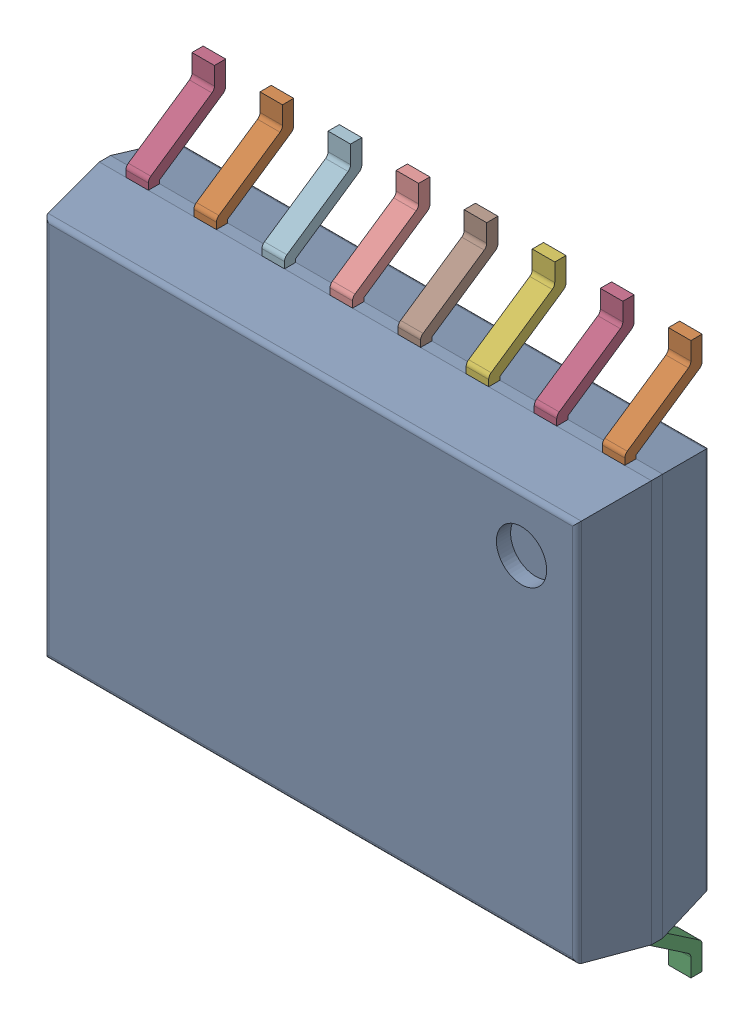
SolidWorks assembly IC6_3.step, configuration Default. Lengths in mm.
Overall size (10.3 10.3 2.65).
3 component instances, 2 part files, 0 mates.
Components (placement in the parent):
- 6383678080.step-1: 6383678080.step [Default] at (114.154 101.326 0) x (0 -1 0) z (0 0 1) size (10.3 10.3 2.65)
  - Body-0_3.step-14: Body-0_3.step [Default] at origin size (7.5 10.3 2.48)
  - PinsArrayLR_4.step-14: PinsArrayLR_4.step [Default] at origin size (10.3 9.31 1.44)
